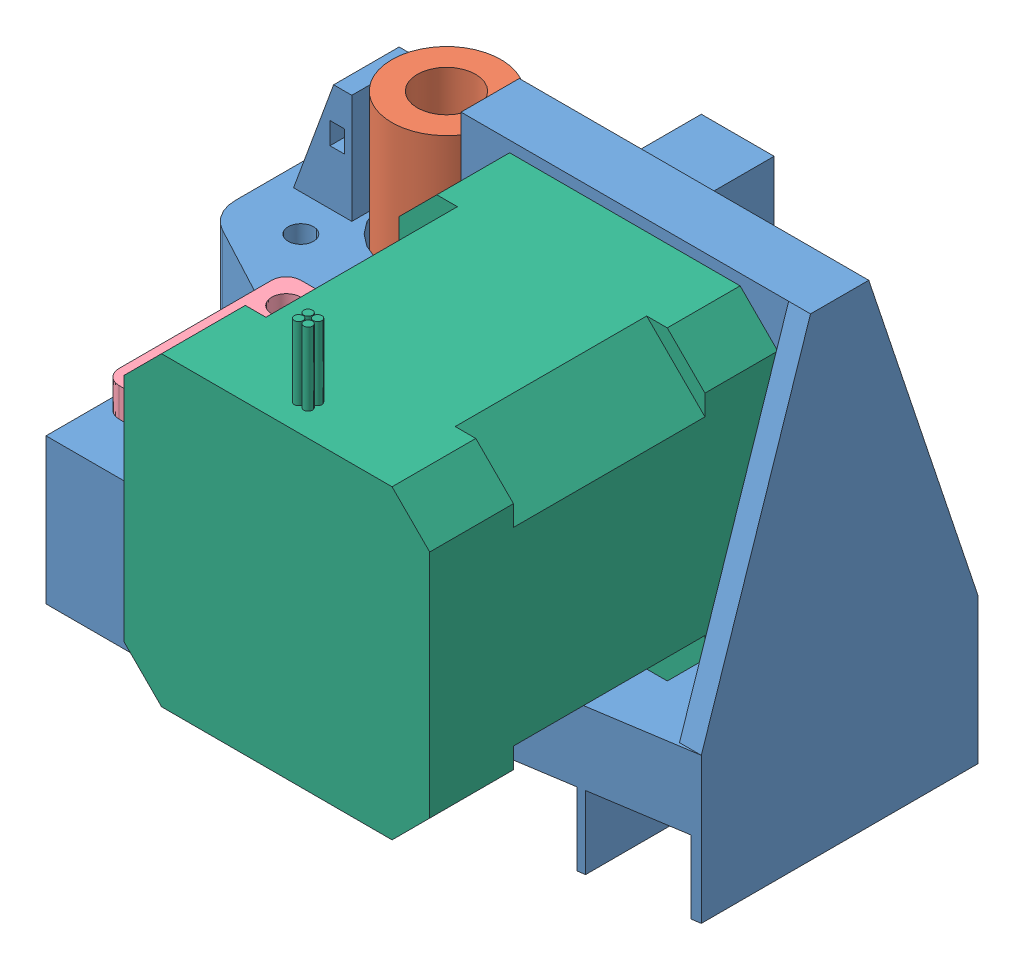
SolidWorks assembly Z left platform, configuration Default. Lengths in mm.
Overall size (98 95.5 95.8).
10 component instances, 7 part files, 23 mates.
Components (placement in the parent):
- Z left move-1: Z left move [Default] at (-42.9453 -12.3877 31.0777) size (98 66.1 70)
- LM8UU 8 mm linear bearing-1: LM8UU 8 mm linear bearing [Default] at (-24.4453 -39.3877 -20.4223) x (-0.198048 0 -0.980192) z (0 1 0) size (15 15 24)
- M8 nut-2: M8 nut [Default] at (-10.4453 -7.3877 12.0777) size (15 6 12.99)
- nut holder-1: nut holder [Default] at (-26.4453 -1.8877 24.5777) size (32 4 25)
- linear holder-1: linear holder [Default] at (-38.4453 -44.3877 -6.4223) size (28 15 28)
- stepper-motor-nema17-fl42sth47-1684A-01-1: stepper-motor-nema17-fl42sth47-1684A-01 [Default] at (29.5547 20.1123 56.8777) x (0 -1 0) z (0 0 -1) size (52 42 71.8)
- pulley T2.5 16 teeth-1: pulley T2.5 16 teeth [Default] at (29.5547 20.1123 6.1777) x (0.850704 -0.525644 0) z (0.525644 0.850704 0) size (16 18.1 16)
- LM8UU 8 mm linear bearing-2: LM8UU 8 mm linear bearing [Default] at (-24.4453 14.6123 -20.4223) x (1 0 0) z (0 -1 0) size (15 15 24)
- M8 nut-3: M8 nut [Default] at (-10.4453 -23.3877 12.0777) size (15 6 12.99)
- nut holder-2: nut holder [Default] at (5.5547 -22.8877 24.5777) x (-1 0 0) z (0 0 1) size (32 4 25)
Mates (geometry in assembly coordinates):
- Concentric4: concentric anti-aligned: cylinder of Z left move-1 through (-10.4453 -22.3877 12.0777) axis (0 1 0) radius 4.75; cylinder of M8 nut-2 through (-10.4453 -1.3877 12.0777) axis (0 -1 0) radius 4
- Coincident4: coincident anti-aligned: plane of Z left move-1 through (-6.6203 -7.3877 5.4526) normal (0 1 0); plane of M8 nut-2 through (-6.6953 -7.3877 18.5728) normal (0 -1 0)
- Parallel1: parallel anti-aligned: plane of Z left move-1 through (-18.0953 -7.3877 12.0777) normal (0.866025 0 -0.5); plane of M8 nut-2 through (-17.9453 -1.3877 12.0777) normal (-0.866025 0 0.5)
- Concentric6: concentric anti-aligned: cylinder of M8 nut-2 through (-10.4453 -1.3877 12.0777) axis (0 -1 0) radius 4; cylinder of nut holder-1 through (-10.4453 -1.8877 12.0777) axis (0 1 0) radius 4.75
- Parallel2: parallel anti-aligned: plane of M8 nut-2 through (-6.6953 -1.3877 5.5825) normal (0 0 -1); plane of nut holder-1 through (-14.2703 -1.3877 5.4526) normal (0 0 1)
- Coincident8: coincident anti-aligned: plane of M8 nut-2 through (-6.6953 -1.3877 18.5728) normal (0 1 0); plane of nut holder-1 through (-6.6203 -1.3877 18.7028) normal (0 -1 0)
- Concentric13: concentric aligned: cylinder of Z left move-1 through (45.0547 35.6123 31.0777) axis (0 0 -1) radius 2; cylinder of stepper-motor-nema17-fl42sth47-1684A-01-1 through (45.0547 35.6123 9.0777) axis (0 0 -1) radius 1.2295
- Concentric14: concentric aligned: cylinder of Z left move-1 through (14.0547 4.6123 31.0777) axis (0 0 -1) radius 2; cylinder of stepper-motor-nema17-fl42sth47-1684A-01-1 through (14.0547 4.6123 9.0777) axis (0 0 -1) radius 1.2295
- Coincident10: coincident anti-aligned: plane of Z left move-1 through (7.0547 42.6123 9.0777) normal (0 0 1); plane of stepper-motor-nema17-fl42sth47-1684A-01-1 through (8.5547 -0.8877 9.0777) normal (0 0 -1)
- Concentric15: concentric anti-aligned: cylinder of stepper-motor-nema17-fl42sth47-1684A-01-1 through (29.5547 20.1123 -14.9223) axis (0 0 1) radius 2.5; cylinder of pulley T2.5 16 teeth-1 through (29.5547 20.1123 6.1777) axis (0 0 -1) radius 2.5
- Concentric16: concentric aligned: cylinder of LM8UU 8 mm linear bearing-1 through (-24.4453 -39.3877 -20.4223) axis (0 1 0) radius 4; cylinder of linear holder-1 through (-24.4453 -39.3877 -20.4223) axis (0 1 0) radius 8
- Concentric17: concentric aligned: cylinder of Z left move-1 through (-24.4453 -22.3877 -20.4223) axis (0 1 0) radius 5; cylinder of LM8UU 8 mm linear bearing-1 through (-24.4453 -39.3877 -20.4223) axis (0 1 0) radius 4
- Coincident12: coincident anti-aligned: plane of LM8UU 8 mm linear bearing-1 through (-24.4453 -39.3877 -20.4223) normal (0 -1 0); plane of linear holder-1 through (-24.4453 -39.3877 -20.4223) normal (0 1 0)
- Coincident13: coincident anti-aligned: plane of Z left move-1 through (-24.4453 -15.3877 -20.4223) normal (0 -1 0); plane of LM8UU 8 mm linear bearing-1 through (-24.4453 -15.3877 -20.4223) normal (0 1 0)
- Concentric18: concentric anti-aligned: cylinder of Z left move-1 through (-24.4453 -22.3877 -20.4223) axis (0 1 0) radius 5; cylinder of LM8UU 8 mm linear bearing-2 through (-24.4453 14.6123 -20.4223) axis (0 -1 0) radius 4
- Coincident14: coincident anti-aligned: plane of Z left move-1 through (-24.4453 -9.3877 -20.4223) normal (0 1 0); plane of LM8UU 8 mm linear bearing-2 through (-24.4453 -9.3877 -20.4223) normal (0 -1 0)
- Concentric19: concentric anti-aligned: cylinder of Z left move-1 through (-10.4453 -22.3877 12.0777) axis (0 1 0) radius 4.75; cylinder of M8 nut-3 through (-10.4453 -17.3877 12.0777) axis (0 -1 0) radius 4
- Parallel3: parallel anti-aligned: plane of Z left move-1 through (-14.2703 -17.3877 18.7028) normal (0.866025 0 -0.5); plane of M8 nut-3 through (-17.9453 -17.3877 12.0777) normal (-0.866025 0 0.5)
- Coincident16: coincident anti-aligned: plane of Z left move-1 through (-6.6203 -17.3877 18.7028) normal (0 -1 0); plane of M8 nut-3 through (-6.6953 -17.3877 18.5728) normal (0 1 0)
- Concentric20: concentric aligned: cylinder of M8 nut-3 through (-10.4453 -17.3877 12.0777) axis (0 -1 0) radius 4; cylinder of nut holder-2 through (-10.4453 -22.8877 12.0777) axis (0 -1 0) radius 4.75
- Parallel4: parallel anti-aligned: plane of M8 nut-3 through (-14.1953 -17.3877 5.5825) normal (-0.866025 0 -0.5); plane of nut holder-2 through (-14.2703 -23.3877 5.4526) normal (0.866025 0 0.5)
- Coincident18: coincident anti-aligned: plane of M8 nut-3 through (-6.6953 -23.3877 18.5728) normal (0 -1 0); plane of nut holder-2 through (-14.2703 -23.3877 18.7028) normal (0 1 0)
- Distance2: distance = 3 mm aligned: plane of pulley T2.5 16 teeth-1 through (29.5547 20.1123 -11.9223) normal (0 0 -1); plane of stepper-motor-nema17-fl42sth47-1684A-01-1 through (29.5547 17.6123 -14.9223) normal (0 0 -1)
